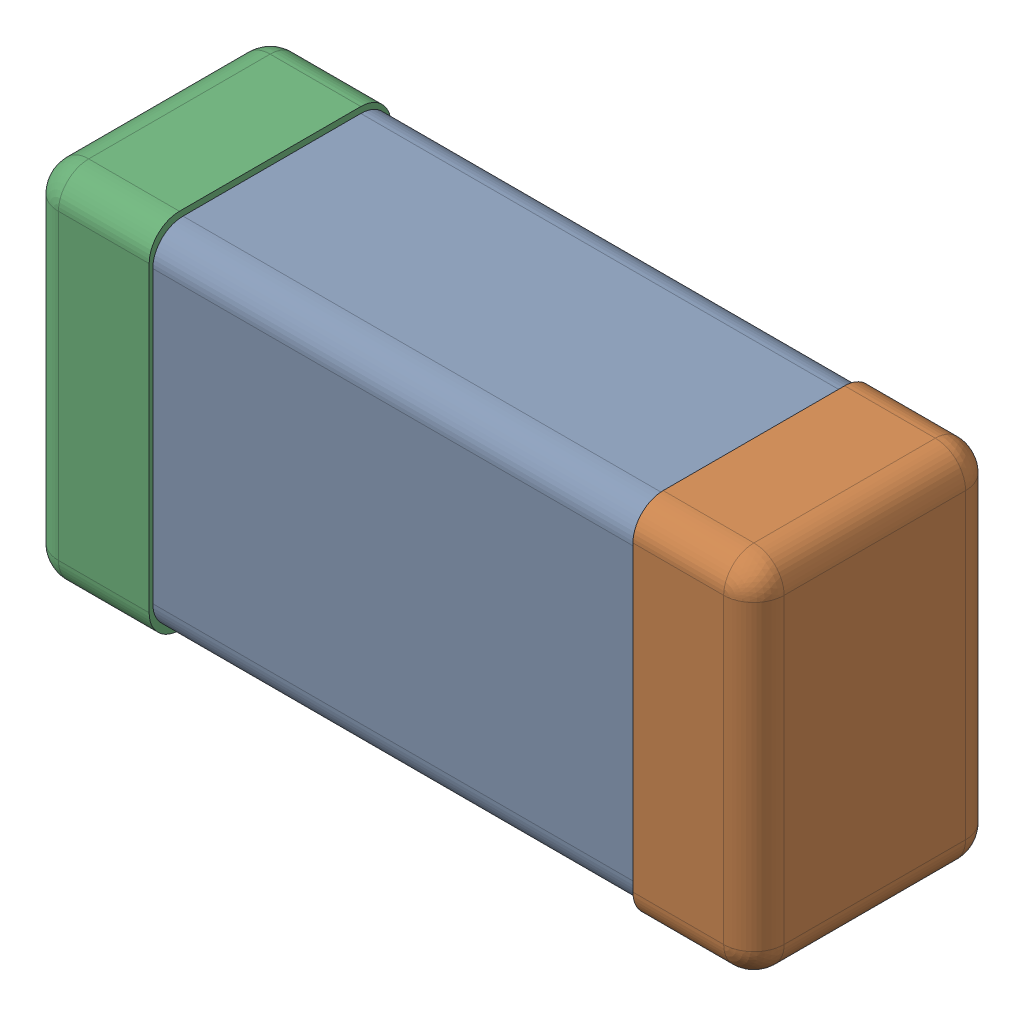
SolidWorks assembly C0201_020_14, configuration Standard. Lengths in mm.
Overall size (0.6 0.3 0.2).
4 component instances, 3 part files, 0 mates.
Components (placement in the parent):
- C0201_020_15-1: C0201_020_15 [Standard] at origin size (0.6 0.3 0.2)
  - Part 3_2-1: Part 3_2 [Standard] at (0 0 -7.3015) size (0.5 0.29 0.2)
  - Part 2_2-1: Part 2_2 [Standard] at (0 0 -7.3) size (0.1 0.3 0.2)
  - Part 1_2-1: Part 1_2 [Standard] at (0 0 -7.3) size (0.1 0.3 0.2)
